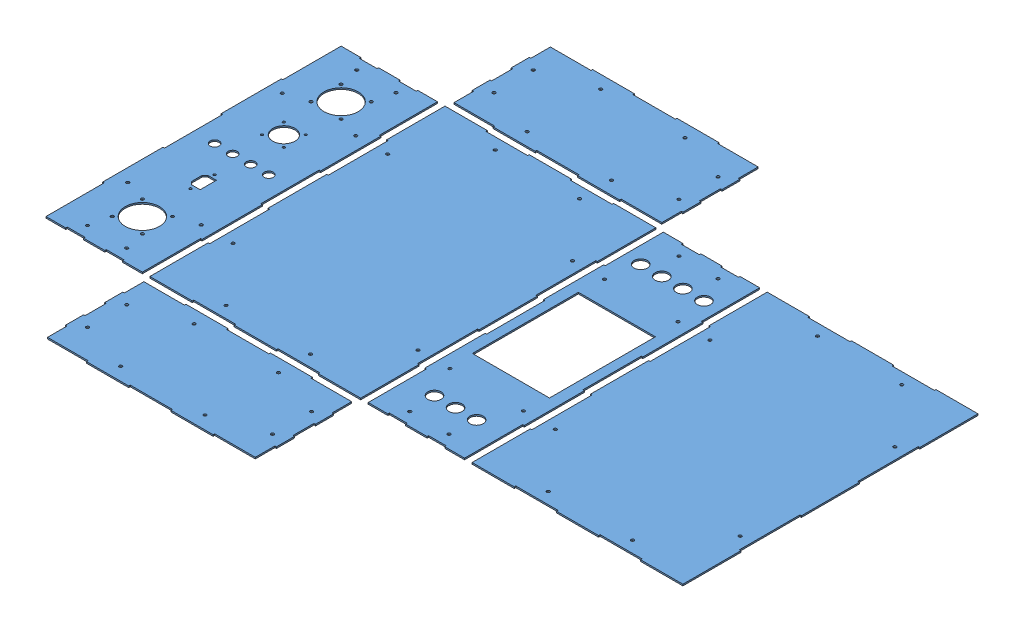
SolidWorks assembly cutting, configuration Default. Lengths in mm.
Overall size (1060 2.5 840).
7 component instances, 7 part files, 15 mates.
Components (placement in the parent):
- Bottom-1: Bottom [Default] at origin size (350 2.5 490) (hidden)
- Front-1: Front [Default] at (0 2.5 337.5) x (-1 0 0) z (0 -1 0) size (350 165 2.5) (hidden)
- Back-1: Back [Default] at (0 0 -337.5) x (-1 0 0) z (0 1 0) size (350 165 2.5) (hidden)
- Lat_Left-1: Lat_Left [Default] at (-267.5 0 0) x (0 1 0) z (0 0 1) size (2.5 165 490) (hidden)
- Lat_Right-1: Lat_Right [Default] at (267.5 2.5 0) x (0 -1 0) z (0 0 1) size (2.5 165 490) (hidden)
- Top-1: Top [Default] at (535 0 0) size (350 2.5 490) (hidden)
- Part1^cutting-1: Part1^cutting [Default] at origin size (1060 2.5 840) (virtual)
Mates (geometry in assembly coordinates):
- Coincident4: coincident aligned: plane of Bottom-1 through (0 2.5 0) normal (0 1 0); plane of Front-1 through (0 2.5 337.5) normal (0 1 0)
- Distance2: distance anti-aligned: plane of Front-1 through (-105 0 255) normal (0 0 -1); plane of Bottom-1 through (-175 2.5 245) normal (0 0 1)
- Coincident6: coincident aligned: plane of Bottom-1 through (-175 2.5 -245) normal (-1 0 0); plane of Front-1 through (-175 0 290) normal (-1 0 0)
- Coincident7: coincident aligned: plane of Bottom-1 through (0 2.5 0) normal (0 1 0); plane of Back-1 through (0 2.5 -337.5) normal (0 1 0)
- Distance3: distance anti-aligned: plane of Back-1 through (105 2.5 -255) normal (0 0 1); plane of Bottom-1 through (-175 2.5 -245) normal (0 0 -1)
- Coincident8: coincident aligned: plane of Bottom-1 through (-175 2.5 -245) normal (-1 0 0); plane of Back-1 through (-175 2.5 -290) normal (-1 0 0)
- Coincident9: coincident aligned: plane of Bottom-1 through (0 2.5 0) normal (0 1 0); plane of Lat_Left-1 through (-267.5 2.5 0) normal (0 1 0)
- Distance4: distance anti-aligned: plane of Lat_Left-1 through (-185 2.5 148.3333) normal (1 0 0); plane of Bottom-1 through (-175 2.5 -245) normal (-1 0 0)
- Coincident10: coincident aligned: plane of Bottom-1 through (-175 2.5 245) normal (0 0 1); plane of Lat_Left-1 through (-187.5 2.5 245) normal (0 0 1)
- Coincident11: coincident aligned: plane of Bottom-1 through (0 2.5 0) normal (0 1 0); plane of Lat_Right-1 through (267.5 2.5 0) normal (0 1 0)
- Distance5: distance anti-aligned: plane of Lat_Right-1 through (185 0 148.3333) normal (-1 0 0); plane of Bottom-1 through (175 2.5 -245) normal (1 0 0)
- Coincident12: coincident aligned: plane of Bottom-1 through (-175 2.5 245) normal (0 0 1); plane of Lat_Right-1 through (187.5 0 245) normal (0 0 1)
- Coincident13: coincident aligned: plane of Lat_Right-1 through (267.5 2.5 0) normal (0 1 0); plane of Top-1 through (535 2.5 0) normal (0 1 0)
- Distance6: distance anti-aligned: plane of Top-1 through (360 2.5 -245) normal (-1 0 0); plane of Lat_Right-1 through (350 0 148.3333) normal (1 0 0)
- Coincident15: coincident aligned: plane of Lat_Right-1 through (187.5 0 245) normal (0 0 1); plane of Top-1 through (360 2.5 245) normal (0 0 1)
